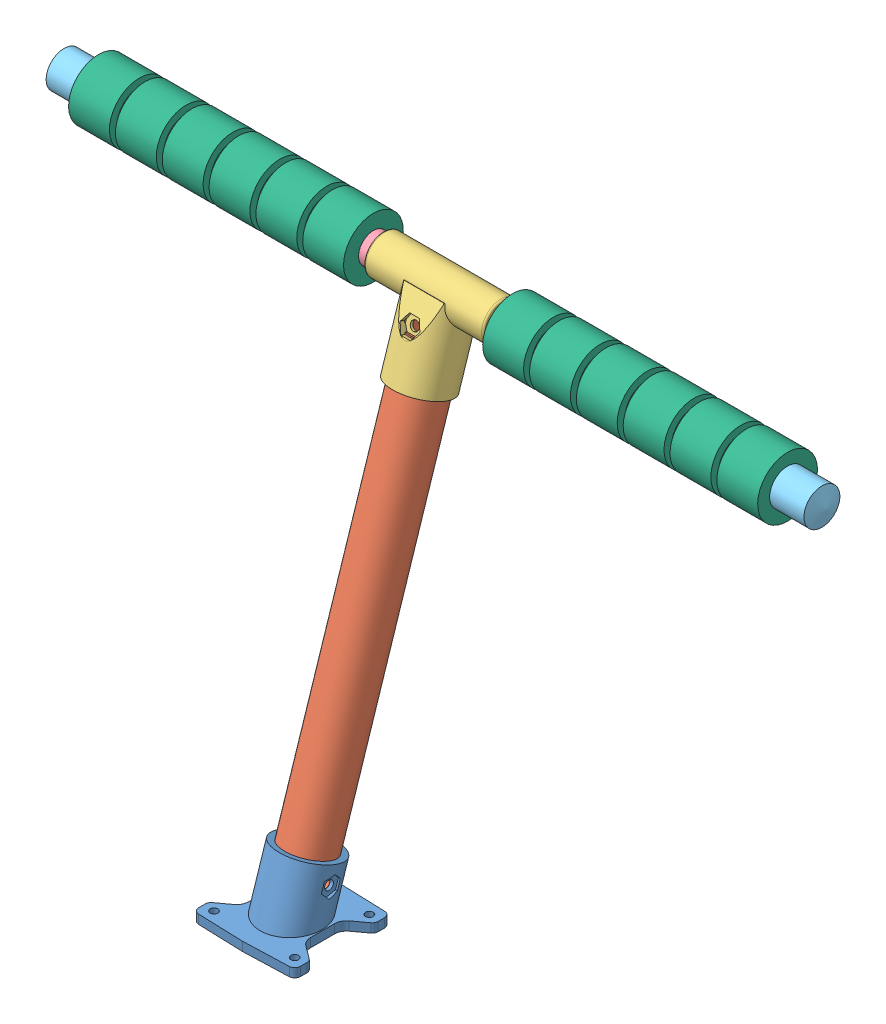
SolidWorks assembly 腳腳, configuration 預設. Lengths in mm.
Overall size (256.56 172.11 80.51).
8 component instances, 6 part files, 15 mates.
Components (placement in the parent):
- 支腳上接點-1: 支腳上接點 [預設] at (47.7741 3.0394 0) size (34 22.5 33)
- 支腳碳棒-1: 支腳碳棒 [預設] at (47.7741 8.7498 -0.8958) x (0 -0.309086 -0.951034) z (0 0.951034 -0.309086) size (16 16 149.6)
- 支腳下接點-1: 支腳下接點 [預設] at (47.7741 137.7101 -42.8078) x (1 0 0) z (0 -0.951034 0.309086) size (40 19 31.8)
- 腳腳碳棒-1: 腳腳碳棒 [預設] at (47.7741 161.7712 -50.6277) x (1 0 0) z (0 0.85349 0.52111) size (252 10 10)
- 腳腳套-1: 腳腳套 [預設] at (176.0549 161.7712 -50.6277) x (-1 0 0) z (0 -0.646345 -0.763045) size (13 12 12)
- 腳腳套-2: 腳腳套 [預設] at (-80.5067 161.7712 -50.6277) x (1 0 0) z (0 -0.836822 -0.547475) size (13 12 12)
- 腳架長圓軟腳-1: 腳架長圓軟腳 [預設] at (-21.5067 161.7712 -50.6277) x (1 0 0) z (0 0.897797 -0.440409) size (92 20 20)
- 腳架長圓軟腳-2: 腳架長圓軟腳 [預設] at (117.0549 161.7712 -50.6277) x (1 0 0) z (0 -0.994091 -0.108552) size (92 20 20)
Mates (geometry in assembly coordinates):
- 同軸心1: concentric anti-aligned: cylinder of 支腳上接點-1 through (47.7741 -16.034 7.159) axis (0 0.951034 -0.309086) radius 8; cylinder of 支腳碳棒-1 through (47.7741 151.0245 -47.135) axis (0 -0.951034 0.309086) radius 8
- 同軸心2: concentric anti-aligned: cylinder of 支腳上接點-1 through (30.7741 16.7385 -3.4921) axis (1 0 0) radius 1.5; cylinder of 支腳碳棒-1 through (55.7741 16.7385 -3.4921) axis (-1 0 0) radius 1.4
- 同軸心3: concentric aligned: cylinder of 支腳碳棒-1 through (47.7741 151.0245 -47.135) axis (0 -0.951034 0.309086) radius 8; cylinder of 支腳下接點-1 through (47.7741 167.9539 -52.6371) axis (0 -0.951034 0.309086) radius 8
- 重合/共線/共點1: coincident anti-aligned: plane of 支腳碳棒-1 through (47.7741 151.0245 -47.135) normal (0 0.951034 -0.309086); plane of 支腳下接點-1 through (44.7741 -154392.0116 -475564.1694) normal (0 -0.951034 0.309086)
- 平行(R)1: parallel aligned: plane of 支腳上接點-1 through (56.7741 14.3357 -5.6553) normal (0 0.309086 0.951034); plane of 支腳下接點-1 through (47.7741 139.8737 -36.1506) normal (0 0.309086 0.951034)
- 同軸心4: concentric aligned: cylinder of 支腳下接點-1 through (67.7741 161.7712 -50.6277) axis (-1 0 0) radius 5.1; cylinder of 腳腳碳棒-1 through (173.7741 161.7712 -50.6277) axis (-1 0 0) radius 5
- 重合/共線/共點3: coincident aligned: plane of 支腳下接點-1; plane of 腳腳碳棒-1
- 同軸心5: concentric aligned: cylinder of 腳腳碳棒-1 through (173.7741 161.7712 -50.6277) axis (-1 0 0) radius 5; cylinder of 腳架長圓軟腳-1 through (24.4933 161.7712 -50.6277) axis (-1 0 0) radius 5
- 同軸心6: concentric aligned: cylinder of 腳腳碳棒-1 through (173.7741 161.7712 -50.6277) axis (-1 0 0) radius 5; cylinder of 腳架長圓軟腳-2 through (163.0549 161.7712 -50.6277) axis (-1 0 0) radius 5
- 同軸心7: concentric aligned: cylinder of 腳腳碳棒-1 through (173.7741 161.7712 -50.6277) axis (-1 0 0) radius 5; cylinder of 腳腳套-2 through (-67.5067 161.7712 -50.6277) axis (-1 0 0) radius 5
- 重合/共線/共點4: coincident anti-aligned: plane of 腳腳碳棒-1 through (-78.2259 161.7712 -50.6277) normal (-1 0 0); circle of 腳腳套-2
- 同軸心8: concentric anti-aligned: cylinder of 腳腳碳棒-1 through (173.7741 161.7712 -50.6277) axis (-1 0 0) radius 5; cylinder of 腳腳套-1 through (163.0549 161.7712 -50.6277) axis (1 0 0) radius 5
- 重合/共線/共點5: coincident anti-aligned: plane of 腳腳碳棒-1 through (173.7741 161.7712 -50.6277) normal (1 0 0); circle of 腳腳套-1
- 重合/共線/共點6: coincident anti-aligned: plane of 腳腳套-1 through (163.0549 161.7712 -50.6277) normal (-1 0 0); plane of 腳架長圓軟腳-2 through (163.0549 161.7712 -50.6277) normal (1 0 0)
- 重合/共線/共點7: coincident anti-aligned: plane of 腳腳套-2 through (-67.5067 161.7712 -50.6277) normal (1 0 0); plane of 腳架長圓軟腳-1 through (-67.5067 161.7712 -50.6277) normal (-1 0 0)
